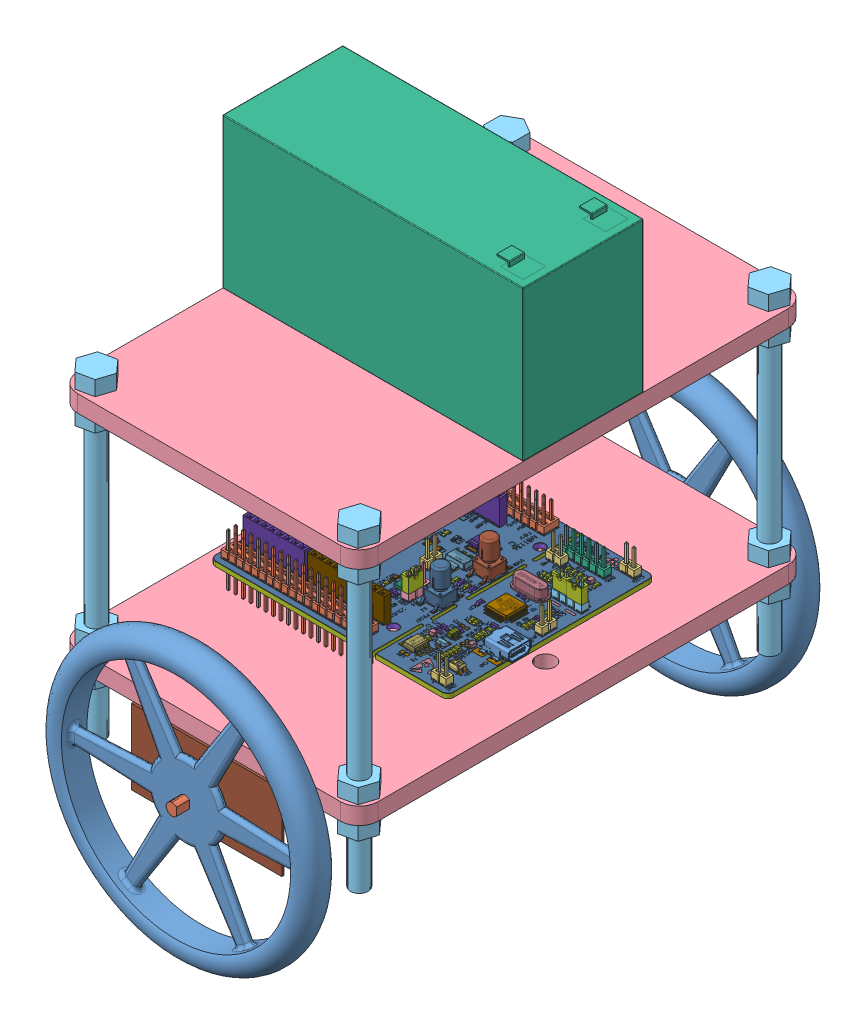
SolidWorks assembly Full Assembly, configuration Default. Lengths in mm.
Overall size (105.56 192.1 176.44).
135 component instances, 47 part files, 38 mates.
Components (placement in the parent):
- Wheel-1: Wheel [Default] at (0 0 82.55) size (92.5 92.5 10)
- Wheel-2: Wheel [Default] at (0 0 -82.55) size (92.5 92.5 10)
- Motor-1: Motor [Default] at (0 30.875 57.3449) x (0 -1 0) z (0 0 1) size (25 32.85 74)
- Motor-2: Motor [Default] at (0 -30.875 -57.3449) x (0 1 0) z (0 0 -1) size (25 32.85 74)
- Adafruit_BNO055-1: Adafruit_BNO055 [Default] at (13.335 12.5 10.16) x (-1 0 0) z (0 0 1) size (26.67 4.2 20.32)
- Acrylic Base-1: Acrylic Base [Default] at (0 30.05 0) size (101.6 5.71 151.44)
- Acrylic Base-2: Acrylic Base [Default] at (0 105.1025 0) size (101.6 5.71 151.44)
- Bolt Nut Assy-1: Bolt Nut Assy [Default] at origin size (15.16 108 15.27)
  - Bolt Nut-1: Bolt Nut [Bolt] at (44.45 98.2676 69.3699) x (-0.669131 0 -0.743145) z (-0.743145 0 0.669131) size (11.55 108 10)
  - Bolt Nut-2: Bolt Nut [Nut] at (44.45 87.5526 69.3699) x (-0.669131 0 -0.743145) z (-0.743145 0 0.669131) size (11.55 5 10)
  - Bolt Nut-3: Bolt Nut [Nut] at (44.45 23.215 69.3699) x (-0.669131 0 -0.743145) z (-0.743145 0 0.669131) size (11.55 5 10)
  - Bolt Nut-4: Bolt Nut [Nut] at (44.45 12.5 69.3699) x (-0.669131 0 -0.743145) z (-0.743145 0 0.669131) size (11.55 5 10)
- Bolt Nut Assy-3: Bolt Nut Assy [Default] at (0 0 -138.7397) size (15.16 108 15.27)
  - Bolt Nut-1: Bolt Nut [Bolt] at (44.45 98.2676 69.3699) x (-0.669131 0 -0.743145) z (-0.743145 0 0.669131) size (11.55 108 10)
  - Bolt Nut-2: Bolt Nut [Nut] at (44.45 87.5526 69.3699) x (-0.669131 0 -0.743145) z (-0.743145 0 0.669131) size (11.55 5 10)
  - Bolt Nut-3: Bolt Nut [Nut] at (44.45 23.215 69.3699) x (-0.669131 0 -0.743145) z (-0.743145 0 0.669131) size (11.55 5 10)
  - Bolt Nut-4: Bolt Nut [Nut] at (44.45 12.5 69.3699) x (-0.669131 0 -0.743145) z (-0.743145 0 0.669131) size (11.55 5 10)
- Bolt Nut Assy-4: Bolt Nut Assy [Default] at (-121.7282 0 -40.8031) x (0.214105 0 -0.976811) z (0.976811 0 0.214105) size (15.16 108 15.27)
  - Bolt Nut-1: Bolt Nut [Bolt] at (44.45 98.2676 69.3699) x (-0.669131 0 -0.743145) z (-0.743145 0 0.669131) size (11.55 108 10)
  - Bolt Nut-2: Bolt Nut [Nut] at (44.45 87.5526 69.3699) x (-0.669131 0 -0.743145) z (-0.743145 0 0.669131) size (11.55 5 10)
  - Bolt Nut-3: Bolt Nut [Nut] at (44.45 23.215 69.3699) x (-0.669131 0 -0.743145) z (-0.743145 0 0.669131) size (11.55 5 10)
  - Bolt Nut-4: Bolt Nut [Nut] at (44.45 12.5 69.3699) x (-0.669131 0 -0.743145) z (-0.743145 0 0.669131) size (11.55 5 10)
- Bolt Nut Assy-5: Bolt Nut Assy [Default] at (-88.9 0 0) size (15.16 108 15.27)
  - Bolt Nut-1: Bolt Nut [Bolt] at (44.45 98.2676 69.3699) x (-0.669131 0 -0.743145) z (-0.743145 0 0.669131) size (11.55 108 10)
  - Bolt Nut-2: Bolt Nut [Nut] at (44.45 87.5526 69.3699) x (-0.669131 0 -0.743145) z (-0.743145 0 0.669131) size (11.55 5 10)
  - Bolt Nut-3: Bolt Nut [Nut] at (44.45 23.215 69.3699) x (-0.669131 0 -0.743145) z (-0.743145 0 0.669131) size (11.55 5 10)
  - Bolt Nut-4: Bolt Nut [Nut] at (44.45 12.5 69.3699) x (-0.669131 0 -0.743145) z (-0.743145 0 0.669131) size (11.55 5 10)
- Placeholder board-1: Placeholder board [Default] at (0 93.2676 0) size (101.6 52.58 40.64)
- NUCLEO-F411RE.STEP-2: NUCLEO-F411RE.STEP [Default] at (-38.75 27.173 10.1096) x (0 0 1) z (0 1 0) size (70 83.97 20.27)
  - NUCLEO-F411RE_PCB_Varsay_lan.STEP-1: NUCLEO-F411RE_PCB_Varsay_lan.STEP [Default] at origin size (70 82.5 1.5)
  - NUCLEO-F411RE_PCB_HOLEs_Varsay_lan.STEP-1: NUCLEO-F411RE_PCB_HOLEs_Varsay_lan.STEP [Default] at origin size (65.28 79.87 1.57)
  - NUCLEO-F411RE_PCB_TOP_Pads_Varsay_lan.STEP-1: NUCLEO-F411RE_PCB_TOP_Pads_Varsay_lan.STEP [Default] at origin size (59.94 77.1 0.04)
  - NUCLEO-F411RE_PCB_TOP_Solder_Varsay_lan.STEP-1: NUCLEO-F411RE_PCB_TOP_Solder_Varsay_lan.STEP [Default] at origin size (69.8 82.3 0.05)
  - NUCLEO-F411RE_PCB_BOTTOM_Pads_Varsay_lan.STEP-1: NUCLEO-F411RE_PCB_BOTTOM_Pads_Varsay_lan.STEP [Default] at origin size (31.1 70.87 0.04)
  - NUCLEO-F411RE_PCB_BOTTOM_Solder_Varsay_lan.STEP-1: NUCLEO-F411RE_PCB_BOTTOM_Solder_Varsay_lan.STEP [Default] at origin size (69.8 82.3 0.04)
  - NUCLEO-F411RE_PCB_TOP_Overlay_Varsay_lan.STEP-1: NUCLEO-F411RE_PCB_TOP_Overlay_Varsay_lan.STEP [Default] at origin size (68.09 77.67 0)
  - NUCLEO-F411RE_PCB_TOP_Designators_Varsay_lan.STEP-1: NUCLEO-F411RE_PCB_TOP_Designators_Varsay_lan.STEP [Default] at origin size (66.29 79.64 0)
  - NUCLEO-F411RE_PCB_BOTTOM_Overlay_Varsay_lan.STEP-1: NUCLEO-F411RE_PCB_BOTTOM_Overlay_Varsay_lan.STEP [Default] at origin size (40.11 80.77 0)
  - SAMTEC_SSQ-106-01-G-S_for_NUCLEO_Varsay_lan.STEP-1: SAMTEC_SSQ-106-01-G-S_for_NUCLEO_Varsay_lan.STEP [Default] at (-33.02 8.89 0.785) x (0 1 0) z (1 0 0) size (15.75 11.15 2.41)
  - SAMTEC_SSQ-108-01-G-S_for_NUCLEO_Varsay_lan.STEP-1: SAMTEC_SSQ-108-01-G-S_for_NUCLEO_Varsay_lan.STEP [Default] at (-33.02 29.21 0.785) x (0 1 0) z (1 0 0) size (20.83 11.15 2.41)
  - SAMTEC_SSQ-108-01-G-S_for_NUCLEO_Varsay_lan.STEP-2: SAMTEC_SSQ-108-01-G-S_for_NUCLEO_Varsay_lan.STEP [Default] at (15.24 11.43 0.785) x (0 1 0) z (1 0 0) size (20.83 11.15 2.41)
  - SAMTEC_SSQ-110-01-G-S_for_NUCLEO_Varsay_lan.STEP-1: SAMTEC_SSQ-110-01-G-S_for_NUCLEO_Varsay_lan.STEP [Default] at (15.24 35.814 0.785) x (0 1 0) z (1 0 0) size (25.91 11.15 2.41)
  - MOLEX_0678038020_for_NUCLEO.STEP-1: MOLEX_0678038020_for_NUCLEO.STEP [Default] at (3.1721 75.2975 0.785) x (-1 0 0) z (0 1 0) size (9.9 4.95 9)
  - SAMTEC_TSW-119-07-T-D_for_NUCLEO_Varsay_lan.STEP-1: SAMTEC_TSW-119-07-T-D_for_NUCLEO_Varsay_lan.STEP [Default] at (-39.37 25.4 0.785) x (0 -1 0) z (-1 0 0) size (48.26 17.95 5.08)
  - SAMTEC_TSW-119-07-T-D_for_NUCLEO_Varsay_lan.STEP-2: SAMTEC_TSW-119-07-T-D_for_NUCLEO_Varsay_lan.STEP [Default] at (21.59 25.4 0.785) x (0 -1 0) z (-1 0 0) size (48.26 17.95 5.08)
  - SAMTEC_TSW-102-07-T-S_for_NUCLEO_Varsay_lan.STEP-1: SAMTEC_TSW-102-07-T-S_for_NUCLEO_Varsay_lan.STEP [Default] at (-40.64 74.93 0.785) x (0 1 0) z (1 0 0) size (5.08 10.92 2.54)
  - SAMTEC_TSW-102-07-T-S_for_NUCLEO_Varsay_lan.STEP-2: SAMTEC_TSW-102-07-T-S_for_NUCLEO_Varsay_lan.STEP [Default] at (-31.75 59.055 0.785) x (0 -1 0) z (-1 0 0) size (5.08 10.92 2.54)
  - SAMTEC_TSW-102-07-T-S_for_NUCLEO_Varsay_lan.STEP-3: SAMTEC_TSW-102-07-T-S_for_NUCLEO_Varsay_lan.STEP [Default] at (-9.525 77.47 0.785) x (1 0 0) z (0 -1 0) size (5.08 10.92 2.54)
  - SAMTEC_TSW-102-07-T-S_for_NUCLEO_Varsay_lan.STEP-4: SAMTEC_TSW-102-07-T-S_for_NUCLEO_Varsay_lan.STEP [Default] at (-9.525 38.735 0.785) x (1 0 0) z (0 -1 0) size (5.08 10.92 2.54)
  - SAMTEC_TSW-102-07-T-S_for_NUCLEO_Varsay_lan.STEP-5: SAMTEC_TSW-102-07-T-S_for_NUCLEO_Varsay_lan.STEP [Default] at (22.86 74.93 0.785) x (0 -1 0) z (-1 0 0) size (5.08 10.92 2.54)
  - SAMTEC_TSW-103-07-T-S_for_NUCLEO_Varsay_lan.STEP-1: SAMTEC_TSW-103-07-T-S_for_NUCLEO_Varsay_lan.STEP [Default] at (1.905 45.085 0.785) x (1 0 0) z (0 -1 0) size (7.62 10.92 2.54)
  - SAMTEC_TSW-104-07-T-S_for_NUCLEO_Varsay_lan.STEP-1: SAMTEC_TSW-104-07-T-S_for_NUCLEO_Varsay_lan.STEP [Default] at (-21.59 73.66 0.785) x (0 1 0) z (1 0 0) size (10.16 10.92 2.54)
  - SAMTEC_TSW-106-07-T-S_for_NUCLEO_Varsay_lan.STEP-1: SAMTEC_TSW-106-07-T-S_for_NUCLEO_Varsay_lan.STEP [Default] at (-35.56 64.77 0.785) x (0 1 0) z (1 0 0) size (15.24 10.92 2.54)
  - MOLEX_90059-0007.STEP-1: MOLEX_90059-0007.STEP [Default] at (-21.59 76.2 5.75) x (0 1 0) z (1 0 0) size (5.1 4.85 2.54)
  - MOLEX_90059-0007.STEP-2: MOLEX_90059-0007.STEP [Default] at (-21.59 71.12 5.75) x (0 -1 0) z (-1 0 0) size (5.1 4.85 2.54)
  - ST_STM32F411RET6_Varsay_lan.STEP-1: ST_STM32F411RET6_Varsay_lan.STEP [Default] at (-11.4265 21.5935 0.785) x (-1 0 0) z (0 0 -1) size (12 12 1.6)
  - ST_STM32F103CBT6_Varsay_lan.STEP-1: ST_STM32F103CBT6_Varsay_lan.STEP [Default] at (-8.89 64.77 0.785) x (1 0 0) z (0 -1 0) size (9 1.6 9)
  - ESWITCH_TL3301SPF160QGBLK_Varsay_lan.STEP-1: ESWITCH_TL3301SPF160QGBLK_Varsay_lan.STEP [Default] at (-0.635 50.8 0.785) x (0 -1 0) z (-1 0 0) size (6 10.7 10)
  - ESWITCH_TL3301SPF160QGBLU_Varsay_lan.STEP-1: ESWITCH_TL3301SPF160QGBLU_Varsay_lan.STEP [Default] at (-17.145 50.8 0.785) x (0 1 0) z (1 0 0) size (6 10.7 10)
  - ST_STS7PF30L_Varsay_lan.STEP-1: ST_STS7PF30L_Varsay_lan.STEP [Default] at (17.145 60.325 0.785) x (-1 0 0) z (0 1 0) size (4.9 1.75 6)
  - ABRACON_ABL-8.000MHZ-B2_Varsay_lan.STEP-1: ABRACON_ABL-8.000MHZ-B2_Varsay_lan.STEP [Default] at (-18.41 63.4908 0.785) x (0 -1 0) z (-1 0 0) size (11.5 5.57 5)
  - ST_LD1117S50TR_Varsay_lan.STEP-1: ST_LD1117S50TR_Varsay_lan.STEP [Default] at (-14.6685 43.18 0.785) x (0 -1 0) z (-1 0 0) size (6.5 1.9 7)
  - ST_LD39050PU33R_Varsay_lan.STEP-1: ST_LD39050PU33R_Varsay_lan.STEP [Default] at (1.905 40.64 0.785) x (0 1 0) z (1 0 0) size (3 1 3)
  - ST_LD3985M33R_Varsay_lan.STEP-1: ST_LD3985M33R_Varsay_lan.STEP [Default] at (7.62 63.5 0.785) x (1 0 0) z (0 -1 0) size (2.95 1.45 2.8)
  - KEMET_T491B106K025AT_Varsay_lan.STEP-1: KEMET_T491B106K025AT_Varsay_lan.STEP [Default] at (-22.86 41.275 0.785) x (0 -1 0) z (-1 0 0) size (2.8 1.9 3.5)
  - ST_STPS2L30A_Varsay_lan.STEP-1: ST_STPS2L30A_Varsay_lan.STEP [Default] at (-22.86 45.085 0.785) x (0 1 0) z (1 0 0) size (2.58 2.3 5.07)
  - KEMET_T491A106K006AT7280_Varsay_lan.STEP-1: KEMET_T491A106K006AT7280_Varsay_lan.STEP [Default] at (-8.255 43.053 0.785) x (1 0 0) z (0 -1 0) size (1.6 1.6 3.2)
  - ABRACON_ABS25-32.768KHZ-6-T_Varsay_lan.STEP-1: ABRACON_ABS25-32.768KHZ-6-T_Varsay_lan.STEP [Default] at (-23.495 6.35 0.785) x (1 0 0) z (0 -1 0) size (8 2.66 4)
  - LUMEX_SML-LX2835IGC-TR.STEP-1: LUMEX_SML-LX2835IGC-TR.STEP [Default] at (16.51 73.66 0.785) x (1 0 0) z (0 -1 0) size (2.7 1.8 3.5)
  - MOLEX_90059-0007.STEP-3: MOLEX_90059-0007.STEP [Default] at (3.175 45.085 5.75) x (-1 0 0) z (0 1 0) size (5.1 4.85 2.54)
  - ST_BAT60JFILM_Varsay_lan.STEP-1: ST_BAT60JFILM_Varsay_lan.STEP [Default] at (-31.115 71.12 0.785) x (0 -1 0) z (-1 0 0) size (1.28 1.17 2.5)
  - ST_BAT60JFILM_Varsay_lan.STEP-2: ST_BAT60JFILM_Varsay_lan.STEP [Default] at (7.62 69.85 0.785) x (0 -1 0) z (-1 0 0) size (1.28 1.17 2.5)
  - NXP_BC847B,215.STEP-1: NXP_BC847B,215.STEP [Default] at (12.065 64.135 0.785) x (0 -1 0) z (-1 0 0) size (2.9 1.1 2.43)
  - ST_BAT60JFILM_Varsay_lan.STEP-3: ST_BAT60JFILM_Varsay_lan.STEP [Default] at (10.795 59.69 0.785) x (1 0 0) z (0 -1 0) size (1.28 1.17 2.5)
  - YAGEO_CC0805KKX7R7BB225.STEP-1: YAGEO_CC0805KKX7R7BB225.STEP [Default] at (0.127 23.495 0.785) x (0 -1 0) z (-1 0 0) size (1.58 1.29 4.06)
  - YAGEO_RC0603JR-070RL.STEP-1: YAGEO_RC0603JR-070RL.STEP [Default] at (17.145 67.945 0.785) x (1 0 0) z (0 -1 0) size (0.8 0.55 2.16)
  - YAGEO_RC0603JR-070RL.STEP-2: YAGEO_RC0603JR-070RL.STEP [Default] at (15.875 67.945 0.785) x (1 0 0) z (0 -1 0) size (0.8 0.55 2.16)
  - YAGEO_RC0603JR-070RL.STEP-3: YAGEO_RC0603JR-070RL.STEP [Default] at (14.605 67.945 0.785) x (1 0 0) z (0 -1 0) size (0.8 0.55 2.16)
  - YAGEO_RC0603JR-070RL.STEP-4: YAGEO_RC0603JR-070RL.STEP [Default] at (13.335 67.945 0.785) x (1 0 0) z (0 -1 0) size (0.8 0.55 2.16)
  - YAGEO_RC0603JR-070RL.STEP-5: YAGEO_RC0603JR-070RL.STEP [Default] at (12.065 67.945 0.785) x (1 0 0) z (0 -1 0) size (0.8 0.55 2.16)
  - YAGEO_RC0603JR-070RL.STEP-6: YAGEO_RC0603JR-070RL.STEP [Default] at (10.795 67.945 0.785) x (1 0 0) z (0 -1 0) size (0.8 0.55 2.16)
  - YAGEO_RC0603JR-070RL.STEP-7: YAGEO_RC0603JR-070RL.STEP [Default] at (12.7 59.7535 0.785) x (1 0 0) z (0 -1 0) size (0.8 0.55 2.16)
  - YAGEO_RC0603JR-070RL.STEP-8: YAGEO_RC0603JR-070RL.STEP [Default] at (4.445 67.945 0.785) x (1 0 0) z (0 -1 0) size (0.8 0.55 2.16)
  - YAGEO_RC0603JR-070RL.STEP-9: YAGEO_RC0603JR-070RL.STEP [Default] at (3.175 67.945 0.785) x (1 0 0) z (0 -1 0) size (0.8 0.55 2.16)
  - YAGEO_RC0603JR-070RL.STEP-10: YAGEO_RC0603JR-070RL.STEP [Default] at (1.905 67.945 0.785) x (1 0 0) z (0 -1 0) size (0.8 0.55 2.16)
  - YAGEO_RC0603JR-070RL.STEP-11: YAGEO_RC0603JR-070RL.STEP [Default] at (0 67.945 0.785) x (1 0 0) z (0 -1 0) size (0.8 0.55 2.16)
  - YAGEO_RC0603JR-070RL.STEP-12: YAGEO_RC0603JR-070RL.STEP [Default] at (-6.985 73.025 0.785) x (1 0 0) z (0 -1 0) size (0.8 0.55 2.16)
  - YAGEO_RC0603JR-070RL.STEP-13: YAGEO_RC0603JR-070RL.STEP [Default] at (-8.255 73.025 0.785) x (1 0 0) z (0 -1 0) size (0.8 0.55 2.16)
  - YAGEO_RC0603JR-070RL.STEP-14: YAGEO_RC0603JR-070RL.STEP [Default] at (-9.525 73.025 0.785) x (1 0 0) z (0 -1 0) size (0.8 0.55 2.16)
  - YAGEO_RC0603JR-070RL.STEP-15: YAGEO_RC0603JR-070RL.STEP [Default] at (-14.605 73.025 0.785) x (1 0 0) z (0 -1 0) size (0.8 0.55 2.16)
  - YAGEO_RC0603JR-070RL.STEP-16: YAGEO_RC0603JR-070RL.STEP [Default] at (-31.115 73.025 0.785) x (0 -1 0) z (-1 0 0) size (0.8 0.55 2.16)
  - YAGEO_RC0603JR-070RL.STEP-17: YAGEO_RC0603JR-070RL.STEP [Default] at (-31.115 69.215 0.785) x (0 -1 0) z (-1 0 0) size (0.8 0.55 2.16)
  - YAGEO_RC0603JR-070RL.STEP-18: YAGEO_RC0603JR-070RL.STEP [Default] at (-31.115 67.31 0.785) x (0 -1 0) z (-1 0 0) size (0.8 0.55 2.16)
  - YAGEO_RC0603JR-070RL.STEP-19: YAGEO_RC0603JR-070RL.STEP [Default] at (-31.115 65.405 0.785) x (0 -1 0) z (-1 0 0) size (0.8 0.55 2.16)
  - YAGEO_RC0603JR-070RL.STEP-20: YAGEO_RC0603JR-070RL.STEP [Default] at (-31.115 63.5 0.785) x (0 -1 0) z (-1 0 0) size (0.8 0.55 2.16)
  - YAGEO_RC0603JR-070RL.STEP-21: YAGEO_RC0603JR-070RL.STEP [Default] at (-25.4 64.77 0.785) x (0 -1 0) z (-1 0 0) size (0.8 0.55 2.16)
  - YAGEO_RC0603JR-070RL.STEP-22: YAGEO_RC0603JR-070RL.STEP [Default] at (-25.4 63.5 0.785) x (0 -1 0) z (-1 0 0) size (0.8 0.55 2.16)
  - YAGEO_RC0603JR-070RL.STEP-23: YAGEO_RC0603JR-070RL.STEP [Default] at (-25.4 62.23 0.785) x (0 -1 0) z (-1 0 0) size (0.8 0.55 2.16)
  - YAGEO_RC0603JR-070RL.STEP-24: YAGEO_RC0603JR-070RL.STEP [Default] at (-25.4 60.96 0.785) x (0 -1 0) z (-1 0 0) size (0.8 0.55 2.16)
  - YAGEO_RC0603JR-070RL.STEP-25: YAGEO_RC0603JR-070RL.STEP [Default] at (-15.875 11.43 0.785) x (1 0 0) z (0 -1 0) size (0.8 0.55 2.16)
  - YAGEO_RC0603JR-070RL.STEP-26: YAGEO_RC0603JR-070RL.STEP [Default] at (-14.605 11.43 0.785) x (1 0 0) z (0 -1 0) size (0.8 0.55 2.16)
  - YAGEO_RC0603JR-070RL.STEP-27: YAGEO_RC0603JR-070RL.STEP [Default] at (-22.225 18.415 0.785) x (1 0 0) z (0 -1 0) size (0.8 0.55 2.16)
  - YAGEO_RC0603JR-070RL.STEP-28: YAGEO_RC0603JR-070RL.STEP [Default] at (-20.955 32.385 0.785) x (0 -1 0) z (-1 0 0) size (0.8 0.55 2.16)
  - YAGEO_RC0603JR-070RL.STEP-29: YAGEO_RC0603JR-070RL.STEP [Default] at (-8.89 51.435 0.785) x (0 -1 0) z (-1 0 0) size (0.8 0.55 2.16)
  - YAGEO_RC0603JR-070RL.STEP-30: YAGEO_RC0603JR-070RL.STEP [Default] at (-8.89 47.625 0.785) x (0 -1 0) z (-1 0 0) size (0.8 0.55 2.16)
  - YAGEO_RC0603JR-070RL.STEP-31: YAGEO_RC0603JR-070RL.STEP [Default] at (3.81 36.83 0.785) x (0 -1 0) z (-1 0 0) size (0.8 0.55 2.16)
  - YAGEO_RC0603JR-070RL.STEP-32: YAGEO_RC0603JR-070RL.STEP [Default] at (0 63.5 0.785) x (0 -1 0) z (-1 0 0) size (0.8 0.55 2.16)
  - YAGEO_RC0603JR-070RL.STEP-33: YAGEO_RC0603JR-070RL.STEP [Default] at (0 62.23 0.785) x (0 -1 0) z (-1 0 0) size (0.8 0.55 2.16)
  - YAGEO_CC0603KRX7R7BB104.STEP-1: YAGEO_CC0603KRX7R7BB104.STEP [Default] at (-11.43 73.025 0.785) x (1 0 0) z (0 -1 0) size (0.8 0.8 2.16)
  - YAGEO_CC0603KRX7R7BB104.STEP-2: YAGEO_CC0603KRX7R7BB104.STEP [Default] at (-1.905 67.945 0.785) x (1 0 0) z (0 -1 0) size (0.8 0.8 2.16)
  - YAGEO_CC0603KRX7R7BB104.STEP-3: YAGEO_CC0603KRX7R7BB104.STEP [Default] at (5.08 62.865 0.785) x (1 0 0) z (0 -1 0) size (0.8 0.8 2.16)
  - YAGEO_CC0603KRX7R7BB104.STEP-4: YAGEO_CC0603KRX7R7BB104.STEP [Default] at (6.985 59.69 0.785) x (1 0 0) z (0 -1 0) size (0.8 0.8 2.16)
  - YAGEO_CC0603KRX7R7BB104.STEP-5: YAGEO_CC0603KRX7R7BB104.STEP [Default] at (8.89 59.69 0.785) x (1 0 0) z (0 -1 0) size (0.8 0.8 2.16)
  - YAGEO_CC0603KRX7R7BB104.STEP-6: YAGEO_CC0603KRX7R7BB104.STEP [Default] at (-21.59 62.23 0.785) x (1 0 0) z (0 -1 0) size (0.8 0.8 2.16)
  - YAGEO_CC0603KRX7R7BB104.STEP-7: YAGEO_CC0603KRX7R7BB104.STEP [Default] at (-21.59 64.77 0.785) x (1 0 0) z (0 -1 0) size (0.8 0.8 2.16)
  - YAGEO_CC0603KRX7R7BB104.STEP-8: YAGEO_CC0603KRX7R7BB104.STEP [Default] at (-15.24 63.5 0.785) x (1 0 0) z (0 -1 0) size (0.8 0.8 2.16)
  - YAGEO_CC0603KRX7R7BB104.STEP-9: YAGEO_CC0603KRX7R7BB104.STEP [Default] at (-6.35 58.42 0.785) x (0 -1 0) z (-1 0 0) size (0.8 0.8 2.16)
  - YAGEO_CC0603KRX7R7BB104.STEP-10: YAGEO_CC0603KRX7R7BB104.STEP [Default] at (-8.89 53.34 0.785) x (0 -1 0) z (-1 0 0) size (0.8 0.8 2.16)
  - YAGEO_CC0603KRX7R7BB104.STEP-11: YAGEO_CC0603KRX7R7BB104.STEP [Default] at (-8.89 49.53 0.785) x (0 -1 0) z (-1 0 0) size (0.8 0.8 2.16)
  - YAGEO_CC0603KRX7R7BB104.STEP-12: YAGEO_CC0603KRX7R7BB104.STEP [Default] at (-2.54 40.64 0.785) x (1 0 0) z (0 -1 0) size (0.8 0.8 2.16)
  - YAGEO_CC0603KRX7R7BB104.STEP-13: YAGEO_CC0603KRX7R7BB104.STEP [Default] at (-1.27 40.64 0.785) x (1 0 0) z (0 -1 0) size (0.8 0.8 2.16)
  - YAGEO_CC0603KRX7R7BB104.STEP-14: YAGEO_CC0603KRX7R7BB104.STEP [Default] at (5.08 40.64 0.785) x (1 0 0) z (0 -1 0) size (0.8 0.8 2.16)
  - YAGEO_CC0603KRX7R7BB104.STEP-15: YAGEO_CC0603KRX7R7BB104.STEP [Default] at (6.35 40.64 0.785) x (1 0 0) z (0 -1 0) size (0.8 0.8 2.16)
  - YAGEO_CC0603KRX7R7BB104.STEP-16: YAGEO_CC0603KRX7R7BB104.STEP [Default] at (-0.6033 27.94 0.785) x (0 -1 0) z (-1 0 0) size (0.8 0.8 2.16)
  - YAGEO_CC0603KRX7R7BB104.STEP-17: YAGEO_CC0603KRX7R7BB104.STEP [Default] at (-17.145 32.385 0.785) x (1 0 0) z (0 -1 0) size (0.8 0.8 2.16)
  - YAGEO_CC0603KRX7R7BB104.STEP-18: YAGEO_CC0603KRX7R7BB104.STEP [Default] at (-20.32 18.415 0.785) x (1 0 0) z (0 -1 0) size (0.8 0.8 2.16)
  - YAGEO_CC0603KRX7R7BB104.STEP-19: YAGEO_CC0603KRX7R7BB104.STEP [Default] at (-17.145 11.43 0.785) x (1 0 0) z (0 -1 0) size (0.8 0.8 2.16)
  - YAGEO_CC0603KRX7R7BB104.STEP-20: YAGEO_CC0603KRX7R7BB104.STEP [Default] at (0 17.78 0.785) x (0 -1 0) z (-1 0 0) size (0.8 0.8 2.16)
  - YAGEO_CC0603KRX7R7BB104.STEP-21: YAGEO_CC0603KRX7R7BB104.STEP [Default] at (-8.636 12.192 0.785) x (0 -1 0) z (-1 0 0) size (0.8 0.8 2.16)
  - YAGEO_CC0603KRX7R7BB104.STEP-22: YAGEO_CC0603KRX7R7BB104.STEP [Default] at (-19.685 2.794 0.785) x (0 -1 0) z (-1 0 0) size (0.8 0.8 2.16)
  - YAGEO_CC0603KRX7R7BB104.STEP-23: YAGEO_CC0603KRX7R7BB104.STEP [Default] at (-19.685 10.795 0.785) x (0 -1 0) z (-1 0 0) size (0.8 0.8 2.16)
  - LUMEX_SML-LX0603SRW-TR.STEP-1: LUMEX_SML-LX0603SRW-TR.STEP [Default] at (0.635 36.83 0.785) x (1 0 0) z (0 -1 0) size (2.17 0.59 0.81)
  - LUMEX_SML-LX0603GW-TR.STEP-1: LUMEX_SML-LX0603GW-TR.STEP [Default] at (-21.1455 35.5597 0.785) x (1 0 0) z (0 -1 0) size (2.17 0.59 0.81)
- Part81^Full Assembly-1: Part81^Full Assembly [Default] at (0 12.5 -76.4819) x (0 -1 0) z (-1 0 0) size (25.4 25.4 50.8) (virtual)
- Part81^Full Assembly-2: Part81^Full Assembly [Default] at (0 12.5 76.4819) x (0 -1 0) z (1 0 0) size (25.4 25.4 50.8) (virtual)
Mates (geometry in assembly coordinates):
- Coincident1: coincident: plane of Wheel-1 through (0 0 82.55) normal (0 0 1); plane of assembly through (0 0 82.55) normal (0 0 1)
- Coincident2: coincident: plane of Wheel-1 through (0 0 82.55) normal (0 1 0); plane of assembly through (0 0 0) normal (0 1 0)
- Coincident3: coincident: plane of Wheel-1 through (0 0 82.55) normal (1 0 0); plane of assembly through (0 0 0) normal (1 0 0)
- Coincident4: coincident: plane of Wheel-2 through (0 0 -82.55) normal (0 0 1); plane of assembly through (0 0 -82.55) normal (0 0 1)
- Coincident5: coincident: plane of Wheel-2 through (0 0 -82.55) normal (0 1 0); plane of assembly through (0 0 0) normal (0 1 0)
- Coincident6: coincident: plane of Wheel-2 through (0 0 -82.55) normal (1 0 0); plane of assembly through (0 0 0) normal (1 0 0)
- Concentric1: concentric: circle of Wheel-1; circle of Motor-1
- Coincident7: coincident: circle of Wheel-1; plane of Motor-1 through (0 0 78.2199) normal (0 0 1)
- Coincident8: coincident: plane of Motor-1 through (0 30.875 57.3449) normal (1 0 0); plane of assembly through (0 0 0) normal (1 0 0)
- Concentric2: concentric: circle of Wheel-2; circle of Motor-2
- Coincident9: coincident: circle of Wheel-2; plane of Motor-2 through (0 0 -78.2199) normal (0 0 -1)
- Coincident10: coincident: plane of Motor-2 through (0 -30.875 -57.3449) normal (1 0 0); plane of assembly through (0 0 0) normal (1 0 0)
- Coincident11: coincident: point of Adafruit_BNO055-1; plane of assembly
- Coincident12: coincident: point of Adafruit_BNO055-1; plane of assembly
- Coincident14: coincident: plane of Adafruit_BNO055-1 through (-10.795 12.5 7.62) normal (0 1 0); plane of Acrylic Base-1 through (44.45 12.5 69.3699) normal (0 -1 0)
- Parallel1: parallel: plane of Adafruit_BNO055-1 through (-13.335 10.85 7.62) normal (-1 0 0); plane of assembly through (0 0 0) normal (1 0 0)
- Concentric3: concentric: cylinder of Acrylic Base-1 through (38.1 18.215 0) axis (0 -1 0) radius 3.175; cylinder of Acrylic Base-2 through (38.1 93.2676 0) axis (0 -1 0) radius 3.175
- Concentric4: concentric: cylinder of Acrylic Base-1 through (-38.1 18.215 0) axis (0 -1 0) radius 3.175; cylinder of Acrylic Base-2 through (-38.1 93.2676 0) axis (0 -1 0) radius 3.175
- Concentric13: concentric: cylinder of Acrylic Base-2 through (44.45 93.2676 69.3699) axis (0 -1 0) radius 2.3813; cylinder of Bolt Nut Assy-1/Bolt Nut-1 through (44.45 -9.7324 69.3699) axis (0 1 0) radius 3
- Coincident28: coincident: plane of Acrylic Base-2 through (44.45 93.2676 69.3699) normal (0 1 0); plane of Bolt Nut Assy-1/Bolt Nut-1 through (44.45 93.2676 69.3699) normal (0 -1 0)
- Coincident29: coincident: plane of Acrylic Base-2 through (44.45 87.5526 69.3699) normal (0 -1 0); plane of Bolt Nut Assy-1/Bolt Nut-2 through (44.45 87.5526 69.3699) normal (0 1 0)
- Coincident30: coincident: plane of Acrylic Base-1 through (44.45 18.215 69.3699) normal (0 1 0); plane of Bolt Nut Assy-1/Bolt Nut-3 through (44.45 18.215 69.3699) normal (0 -1 0)
- Coincident31: coincident: plane of Acrylic Base-1 through (44.45 12.5 69.3699) normal (0 -1 0); plane of Bolt Nut Assy-1/Bolt Nut-4 through (44.45 12.5 69.3699) normal (0 1 0)
- Concentric17: concentric: cylinder of Acrylic Base-2 through (44.45 93.2676 -69.3699) axis (0 -1 0) radius 2.3813; cylinder of Bolt Nut Assy-3/Bolt Nut-1 through (44.45 -9.7324 -69.3699) axis (0 1 0) radius 3
- Coincident32: coincident: plane of Acrylic Base-2 through (44.45 93.2676 69.3699) normal (0 1 0); plane of Bolt Nut Assy-3/Bolt Nut-1 through (44.45 93.2676 -69.3699) normal (0 -1 0)
- Concentric18: concentric: cylinder of Acrylic Base-2 through (-44.45 93.2676 -69.3699) axis (0 -1 0) radius 2.3813; cylinder of Bolt Nut Assy-4/Bolt Nut-1 through (-44.45 -9.7324 -69.3699) axis (0 1 0) radius 3
- Coincident33: coincident: plane of Acrylic Base-2 through (44.45 93.2676 69.3699) normal (0 1 0); plane of Bolt Nut Assy-4/Bolt Nut-1 through (-44.45 93.2676 -69.3699) normal (0 -1 0)
- Concentric19: concentric: cylinder of Acrylic Base-2 through (-44.45 93.2676 69.3699) axis (0 -1 0) radius 2.3813; cylinder of Bolt Nut Assy-5/Bolt Nut-1 through (-44.45 -9.7324 69.3699) axis (0 1 0) radius 3
- Coincident34: coincident: plane of Acrylic Base-2 through (44.45 93.2676 69.3699) normal (0 1 0); plane of Bolt Nut Assy-5/Bolt Nut-1 through (-44.45 93.2676 69.3699) normal (0 -1 0)
- Coincident35: coincident: plane of Placeholder board-1 through (0 93.2676 0) normal (0 0 1); plane of assembly through (0 0 0) normal (0 0 1)
- Coincident36: coincident: plane of Placeholder board-1 through (0 93.2676 0) normal (1 0 0); plane of assembly through (0 0 0) normal (1 0 0)
- Coincident37: coincident: plane of Acrylic Base-2 through (44.45 93.2676 69.3699) normal (0 1 0); plane of Placeholder board-1 through (0 93.2676 0) normal (0 -1 0)
- Symmetric3: symmetric: plane of ? through (-41.25 27.922 -20.2804) normal (-1 0 0); plane of ? through (41.25 27.922 -31.7804) normal (1 0 0)
- Lock1: lock: unknown of Motor-1; unknown of Acrylic Base-1
- Distance3: distance = 8.173 mm: plane of NUCLEO-F411RE.STEP-2/NUCLEO-F411RE_PCB_BOTTOM_Solder_Varsay_lan.STEP-1 through (16.25 26.388 20.2196) normal (0 -1 0); plane of Acrylic Base-1 through (44.45 18.215 69.3699) normal (0 1 0)
- Coincident38: coincident: plane of Acrylic Base-1 through (44.45 12.5 69.3699) normal (0 -1 0); plane of Part81^Full Assembly-1 through (-25.4 12.5 -76.4819) normal (0 1 0)
- Coincident39: coincident: plane of Motor-2 through (0 0 -75.7199) normal (0 0 -1); plane of Part81^Full Assembly-1 through (-25.4 11.738 -75.7199) normal (0 0 1)
- Coincident40: coincident: plane of Part81^Full Assembly-1 through (0 12.5 -76.4819) normal (-1 0 0); plane of assembly through (0 0 0) normal (1 0 0)
